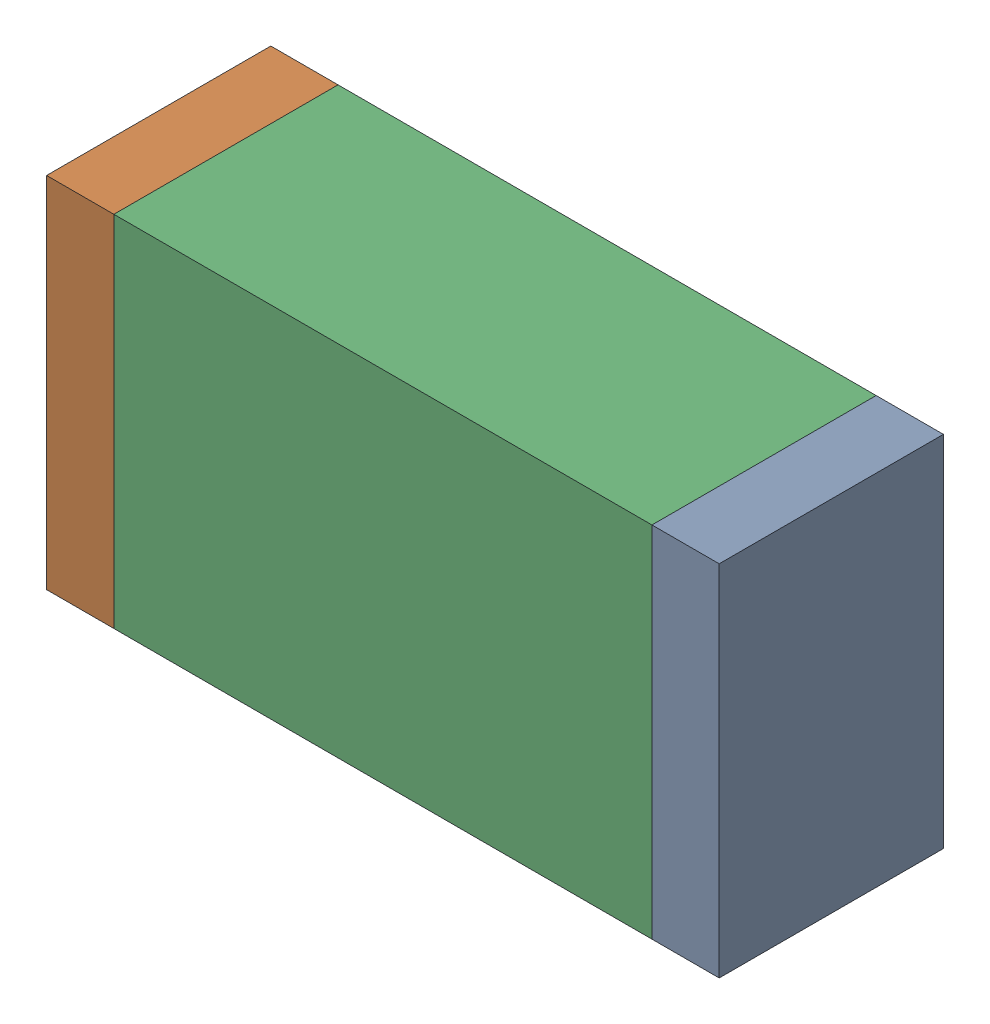
SolidWorks assembly D7, configuration Default. Lengths in mm.
Overall size (1.5 0.8 0.5).
6 component instances, 2 part files, 0 mates.
Components (placement in the parent):
- 836752496-1: 836752496 [Default] at (127.725 14.9 0) size (0.15 0.8 0.5)
  - Extruded_2-1: Extruded_2 [Default] at origin size (0.15 0.8 0.5)
- 836752496-2: 836752496 [Default] at (126.375 14.9 0) size (0.15 0.8 0.5)
  - Extruded_2-1: Extruded_2 [Default] at origin size (0.15 0.8 0.5)
- 836752368-1: 836752368 [Default] at (127.05 14.9 0) size (1.2 0.8 0.5)
  - Extruded-1: Extruded [Default] at origin size (1.2 0.8 0.5)
